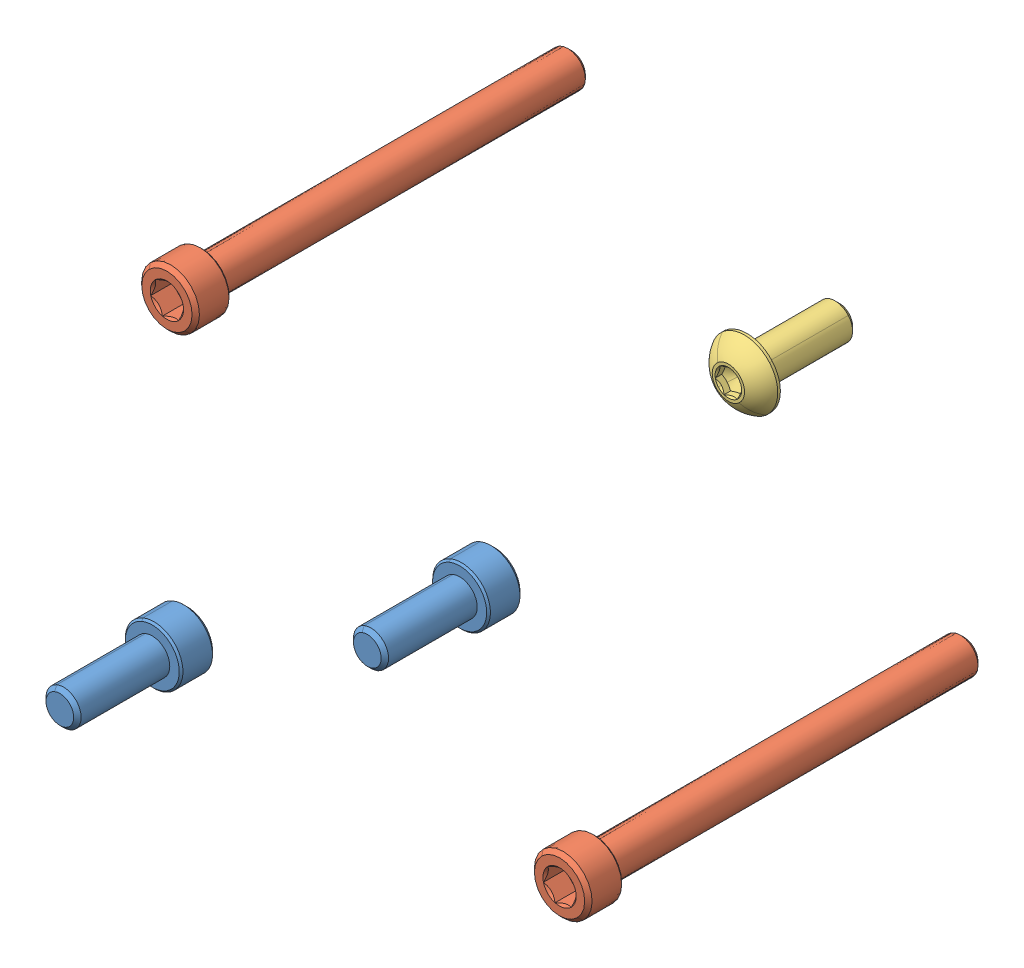
SolidWorks assembly REV-25-2107_3-Stage.STEP, configuration Default. Lengths in mm.
Overall size (65.21 54.09 86.04).
5 component instances, 3 part files, 0 mates.
Components (placement in the parent):
- #10 Socket Head Cap Screws_0.500in Long.STEP-1: #10 Socket Head Cap Screws_0.500in Long.STEP [Default] at (21.1355 14.0872 12.7) x (0.923728 0.383049 0) z (0.383049 -0.923728 0) size (7.94 17.53 7.94)
- #10 Socket Head Cap Screws_0.500in Long.STEP-2: #10 Socket Head Cap Screws_0.500in Long.STEP [Default] at (-21.1355 -14.0872 12.7) x (0.923728 0.383049 0) z (0.383049 -0.923728 0) size (7.94 17.53 7.94)
- #10 Socket Head Cap Screws_2.000in Long.STEP-1: #10 Socket Head Cap Screws_2.000in Long.STEP [Default] at (-26.9919 21.4312 0) x (0.715577 0.698533 0) z (-0.698533 0.715577 0) size (7.94 55.63 7.94)
- #10 Socket Head Cap Screws_2.000in Long.STEP-2: #10 Socket Head Cap Screws_2.000in Long.STEP [Default] at (26.9919 -21.4312 0) x (0.715577 0.698533 0) z (-0.698533 0.715577 0) size (7.94 55.63 7.94)
- #10-32 Button Head Cap Screws_0.500in Long.STEP-1: #10-32 Button Head Cap Screws_0.500in Long.STEP [Default] at (0 0 -47.9425) x (0.655967 -0.754789 0) z (-0.754789 -0.655967 0) size (9.17 15.27 9.17)
